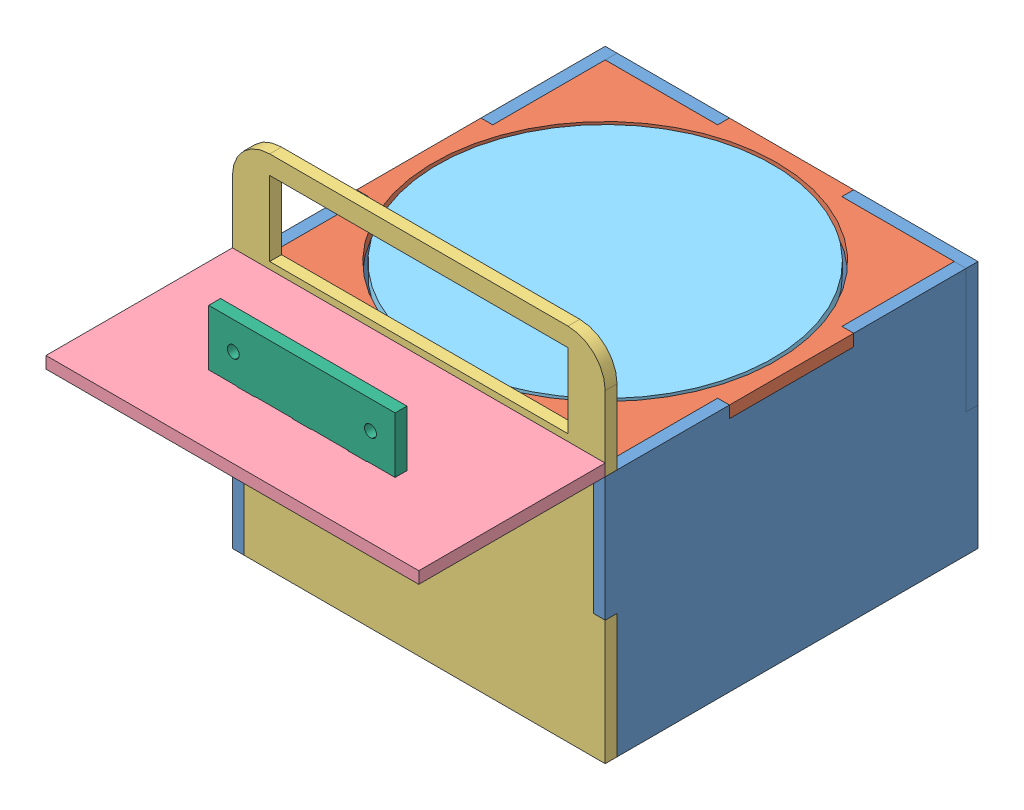
SolidWorks assembly SpinnerBox, configuration Default. Lengths in mm.
Overall size (124.99 96.67 162.5).
13 component instances, 8 part files, 35 mates.
Components (placement in the parent):
- Side Walls-2: Side Walls [Default] at (-9.658 -56.5798 58.2762) x (-1 0 0) z (0 0 -1) size (100 66.67 3.17)
- Side Walls-3: Side Walls [Default] at (37.167 -56.5798 105.1012) x (0 0 -1) z (1 0 0) size (100 66.67 3.17)
- Side Walls-4: Side Walls [Default] at (-56.483 -56.5798 105.1012) x (0 0 1) z (-1 0 0) size (100 66.67 3.17)
- Spinner Top-1: Spinner Top [Default] at (-9.658 -9.7548 105.1012) size (100 3.17 100)
- Sensor Shelf-2: Sensor Shelf [Default] at (-9.658 -56.5798 151.9262) size (100 96.67 3.17)
- Shelf Piece-2: Shelf Piece [Default] at (-9.658 -6.5798 180.1012) x (-1 0 0) z (0 0 -1) size (100 3.17 53.17)
- Spinner Circle - Sarah-1: Spinner Circle - Sarah [Default] at (-9.658 -9.7548 105.1012) x (-0.827871 0 -0.560918) z (0.560918 0 -0.827871) size (90 3.17 90)
- IR Sensor Backboard-1: IR Sensor Backboard [Default] at (-9.4884 4.0952 183.4512) size (50 18.18 3.17)
- MotorFloor-1: MotorFloor [Default] at (-9.658 -73.2465 105.1012) size (93.65 3.17 93.65)
- MotorHug-1: MotorHug [Default] at (-9.658 -66.7381 126.2012) size (40 9.84 3.17)
- MotorHug-2: MotorHug [Default] at (-9.658 -66.7381 80.8262) size (40 9.84 3.17)
- MotorHug-3: MotorHug [Default] at (11.442 -66.7381 105.1012) x (0 0 -1) z (1 0 0) size (40 9.84 3.17)
- MotorHug-4: MotorHug [Default] at (-33.933 -66.7381 105.1012) x (0 0 -1) z (1 0 0) size (40 9.84 3.17)
Mates (geometry in assembly coordinates):
- Coincident4: coincident aligned: plane of Side Walls-2 through (-9.658 -56.5798 55.1012) normal (0 0 -1); plane of Side Walls-3 through (40.342 -73.2465 55.1012) normal (0 0 -1)
- Coincident5: coincident aligned: plane of Side Walls-2 through (40.342 -39.9131 55.1012) normal (1 0 0); plane of Side Walls-3 through (40.342 -56.5798 105.1012) normal (1 0 0)
- Coincident6: coincident aligned: plane of Side Walls-2 through (7.0087 -6.5798 55.1012) normal (0 1 0); plane of Side Walls-3 through (40.342 -6.5798 58.2762) normal (0 1 0)
- Coincident12: coincident aligned: plane of Side Walls-2 through (-56.483 -6.5798 55.1012) normal (0 1 0); plane of Side Walls-4 through (-59.658 -6.5798 88.4345) normal (0 1 0)
- Coincident13: coincident aligned: plane of Side Walls-4 through (-59.658 -6.5798 88.4345) normal (0 1 0); plane of Spinner Top-1 through (-9.658 -6.5798 105.1012) normal (0 1 0)
- Coincident15: coincident aligned: plane of Side Walls-4 through (-59.658 -56.5798 105.1012) normal (-1 0 0); plane of Spinner Top-1 through (-59.658 -6.5798 121.7679) normal (-1 0 0)
- Coincident20: coincident aligned: plane of Side Walls-2 through (-59.658 -73.2465 55.1012) normal (-1 0 0); plane of Side Walls-4 through (-59.658 -56.5798 105.1012) normal (-1 0 0)
- Coincident21: coincident aligned: plane of Side Walls-2 through (-9.658 -56.5798 55.1012) normal (0 0 -1); plane of Spinner Top-1 through (-26.3246 -6.5798 55.1012) normal (0 0 -1)
- Coincident31: coincident anti-aligned: plane of Sensor Shelf-2 through (37.0087 -3.4048 151.9262) normal (0 -1 0); plane of Shelf Piece-2 through (-9.658 -3.4048 180.1012) normal (0 1 0)
- Coincident32: coincident anti-aligned: plane of Sensor Shelf-2 through (37.0087 -6.5798 151.9262) normal (-1 0 0); plane of Shelf Piece-2 through (37.0087 -3.4048 155.1012) normal (1 0 0)
- Coincident33: coincident anti-aligned: plane of Sensor Shelf-2 through (-9.658 -56.5798 155.1012) normal (0 0 1); plane of Shelf Piece-2 through (40.342 -3.4048 155.1012) normal (0 0 -1)
- Coincident34: coincident aligned: plane of Side Walls-3 through (40.342 -56.5798 105.1012) normal (1 0 0); plane of Sensor Shelf-2 through (40.342 -56.5798 155.1012) normal (1 0 0)
- Coincident35: coincident aligned: plane of Side Walls-3 through (40.342 -39.9131 155.1012) normal (0 0 1); plane of Sensor Shelf-2 through (-9.658 -56.5798 155.1012) normal (0 0 1)
- Coincident38: coincident aligned: plane of Spinner Top-1 through (-9.658 -6.5798 105.1012) normal (0 1 0); plane of Spinner Circle - Sarah-1 through (-9.658 -6.5798 105.1012) normal (0 1 0)
- Concentric1: concentric aligned: cylinder of Spinner Top-1 through (-9.658 -6.5798 105.1012) axis (0 -1 0) radius 46; cylinder of Spinner Circle - Sarah-1 through (-9.658 -6.5798 105.1012) axis (0 -1 0) radius 45
- Coincident39: coincident anti-aligned: plane of Shelf Piece-2 through (-21.9884 -6.5798 183.4512) normal (-1 0 0); plane of IR Sensor Backboard-1 through (-21.9884 -3.4048 186.6262) normal (1 0 0)
- Coincident40: coincident anti-aligned: plane of Shelf Piece-2 through (-26.9884 -6.5798 183.4512) normal (0 0 1); plane of IR Sensor Backboard-1 through (-9.4884 4.0952 183.4512) normal (0 0 -1)
- Coincident41: coincident anti-aligned: plane of Shelf Piece-2 through (-9.658 -3.4048 180.1012) normal (0 1 0); plane of IR Sensor Backboard-1 through (-26.9884 -3.4048 186.6262) normal (0 -1 0)
- Coincident42: coincident anti-aligned: plane of Side Walls-4 through (-56.483 -56.5798 105.1012) normal (1 0 0); plane of MotorFloor-1 through (25.7023 -73.2465 49.195) normal (-1 0 0)
- Coincident43: coincident anti-aligned: plane of Side Walls-2 through (-9.658 -56.5798 58.2762) normal (0 0 1); plane of MotorFloor-1 through (119.3523 -73.2465 49.195) normal (0 0 -1)
- Coincident46: coincident anti-aligned: plane of MotorFloor-1 through (72.5273 -73.2465 96.02) normal (0 1 0); plane of MotorHug-4 through (-30.758 -103.4048 90.1012) normal (0 -1 0)
- Coincident47: coincident anti-aligned: plane of MotorFloor-1 through (51.4273 -76.4215 86.02) normal (0 0 -1); plane of MotorHug-4 through (-30.758 -103.4048 95.1012) normal (0 0 1)
- Coincident48: coincident anti-aligned: plane of MotorFloor-1 through (51.4273 -76.4215 86.02) normal (-1 0 0); plane of MotorHug-4 through (-30.758 -100.0715 105.1012) normal (1 0 0)
- Coincident49: coincident anti-aligned: plane of MotorFloor-1 through (62.5273 -76.4215 71.745) normal (0 0 1); plane of MotorHug-2 through (-9.658 -100.0715 80.8262) normal (0 0 -1)
- Coincident50: coincident anti-aligned: plane of MotorFloor-1 through (62.5273 -76.4215 74.92) normal (-1 0 0); plane of MotorHug-2 through (-19.658 -103.4048 84.0012) normal (1 0 0)
- Coincident51: coincident aligned: plane of MotorFloor-1 through (72.5273 -76.4215 96.02) normal (0 -1 0); plane of MotorHug-2 through (-24.658 -106.5798 84.0012) normal (0 -1 0)
- Coincident52: coincident aligned: plane of MotorFloor-1 through (72.5273 -76.4215 96.02) normal (0 -1 0); plane of MotorHug-1 through (-24.658 -106.5798 129.3762) normal (0 -1 0)
- Coincident53: coincident anti-aligned: plane of MotorFloor-1 through (70.0273 -76.4215 117.12) normal (0 0 1); plane of MotorHug-1 through (-9.658 -100.0715 126.2012) normal (0 0 -1)
- Coincident54: coincident anti-aligned: plane of MotorFloor-1 through (82.5273 -76.4215 117.12) normal (1 0 0); plane of MotorHug-1 through (0.342 -103.4048 129.3762) normal (-1 0 0)
- Coincident55: coincident aligned: plane of MotorFloor-1 through (72.5273 -76.4215 96.02) normal (0 -1 0); plane of MotorHug-3 through (14.617 -106.5798 95.1012) normal (0 -1 0)
- Coincident56: coincident anti-aligned: plane of MotorFloor-1 through (93.6273 -76.4215 81.02) normal (1 0 0); plane of MotorHug-3 through (11.442 -100.0715 105.1012) normal (-1 0 0)
- Coincident57: coincident anti-aligned: plane of MotorFloor-1 through (93.6273 -76.4215 86.02) normal (0 0 -1); plane of MotorHug-3 through (14.617 -103.4048 95.1012) normal (0 0 1)
- Coincident58: coincident anti-aligned: plane of Side Walls-4 through (-59.658 -39.9131 155.1012) normal (0 1 0); plane of Sensor Shelf-2 through (-9.658 -39.9131 155.1012) normal (0 -1 0)
- Coincident59: coincident aligned: plane of Side Walls-4 through (-59.658 -73.2465 155.1012) normal (0 0 1); plane of Sensor Shelf-2 through (-9.658 -56.5798 155.1012) normal (0 0 1)
- Coincident61: coincident aligned: plane of Side Walls-3 through (40.342 -73.2465 55.1012) normal (0 -1 0); plane of MotorFloor-1 through (-9.658 -73.2465 105.1012) normal (0 -1 0)
